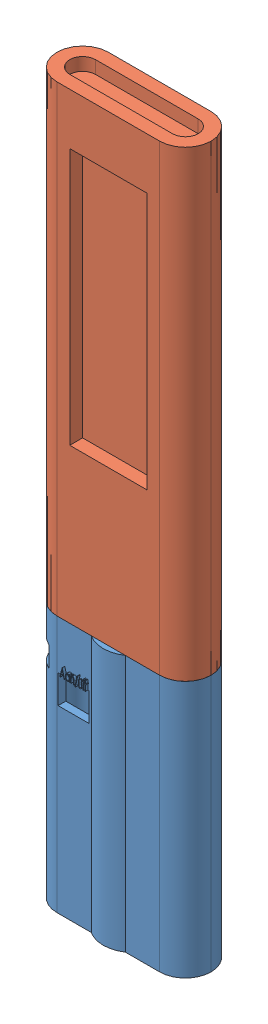
SolidWorks assembly werklamp onderstuk + bovenstuk, configuration Default. Lengths in mm.
Overall size (60 280 24).
2 component instances, 2 part files, 3 mates.
Components (placement in the parent):
- prototype cad handvat werklamp idee 2 kanten bolling-1: prototype cad handvat werklamp idee 2 kanten bolling [Default] at (44.2294 -1.538 83.4813) size (60 108 24)
- prototype_cad_werklamp 1-2: prototype_cad_werklamp 1 [Default] at (44.2294 98.462 83.4813) size (60 180 21)
Mates (geometry in assembly coordinates):
- Coincident1: coincident: plane of prototype cad handvat werklamp idee 2 kanten bolling-1 through (44.2294 98.462 83.4813) normal (0 1 0); plane of prototype_cad_werklamp 1-2 through (104.2294 98.462 83.4813) normal (0 -1 0)
- Coincident2: coincident: plane of prototype cad handvat werklamp idee 2 kanten bolling-1 through (50.8627 98.462 93.4813) normal (0 0 1); plane of prototype_cad_werklamp 1-2 through (134.2294 278.462 93.4813) normal (0 0 1)
- Coincident3: coincident aligned: line of prototype cad handvat werklamp idee 2 kanten bolling-1 through (14.2294 -1.538 83.4813) axis (0 1 0); line of prototype_cad_werklamp 1-2 through (14.2294 98.462 83.4813) axis (0 1 0)
